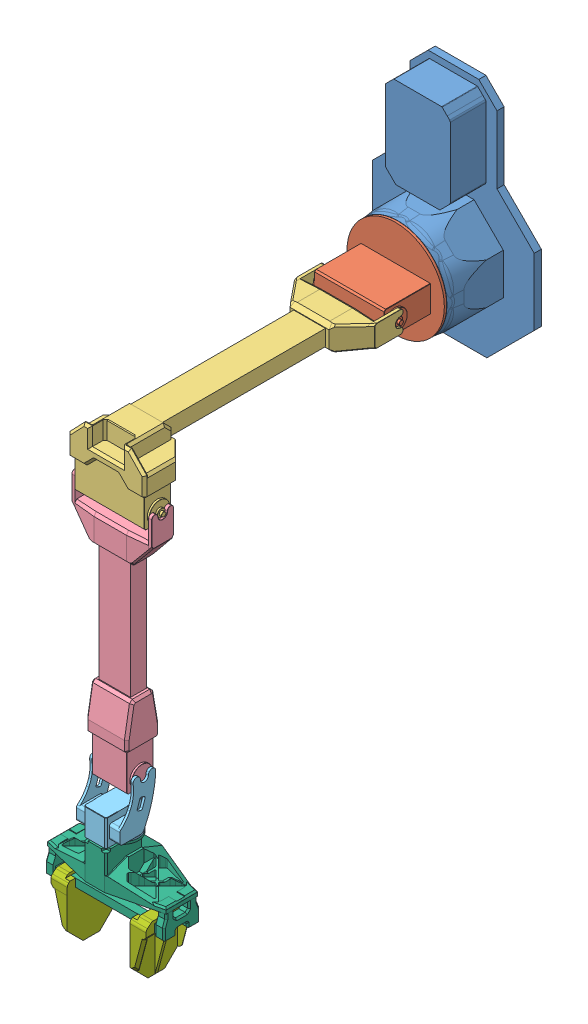
SolidWorks assembly 8 - VXA-300-M, configuration Default. Lengths in mm.
Overall size (204 763.46 462).
9 component instances, 7 part files, 0 mates.
Components (placement in the parent):
- 8 - VXA-300-M.step-1: 8 - VXA-300-M.step [Default] at origin size (204 763.46 462)
  - 540 Base.step-1: 540 Base.step [Default] at origin size (204 299.46 79.72)
  - 540 Dual Shoulder.step-1: 540 Dual Shoulder.step [Default] at (0 0.6326 76) size (123 123 64.5)
  - UA - 8 - VX-300.step-1: UA - 8 - VX-300.step [Default] at (0 0 126.75) size (103.8 89.05 329.69)
  - Fore - 8 - VX-300.step-1: Fore - 8 - VX-300.step [Default] at (0 -59.55 426.75) size (101.2 317.63 41.9)
  - VX-300 - Wrist.step-1: VX-300 - Wrist.step [Default] at (0.1606 -359.55 426.9106) size (55 75.02 55.25)
  - DRG.step-1: DRG.step [Default] at (0 -409.2943 426.75) size (150 76.7 70.3)
  - Carriage-DualRail-VX-ABS.step-1: Carriage-DualRail-VX-ABS.step [Default] at (4.501 -457.7943 426.75) x (1 0 0) z (0 -1 0) size (20.51 61 80.71)
  - Carriage-DualRail-VX-ABS.step-2: Carriage-DualRail-VX-ABS.step [Default] at (-4.499 -457.7943 426.75) x (-1 0 0) z (0 -1 0) size (20.51 61 80.71)
